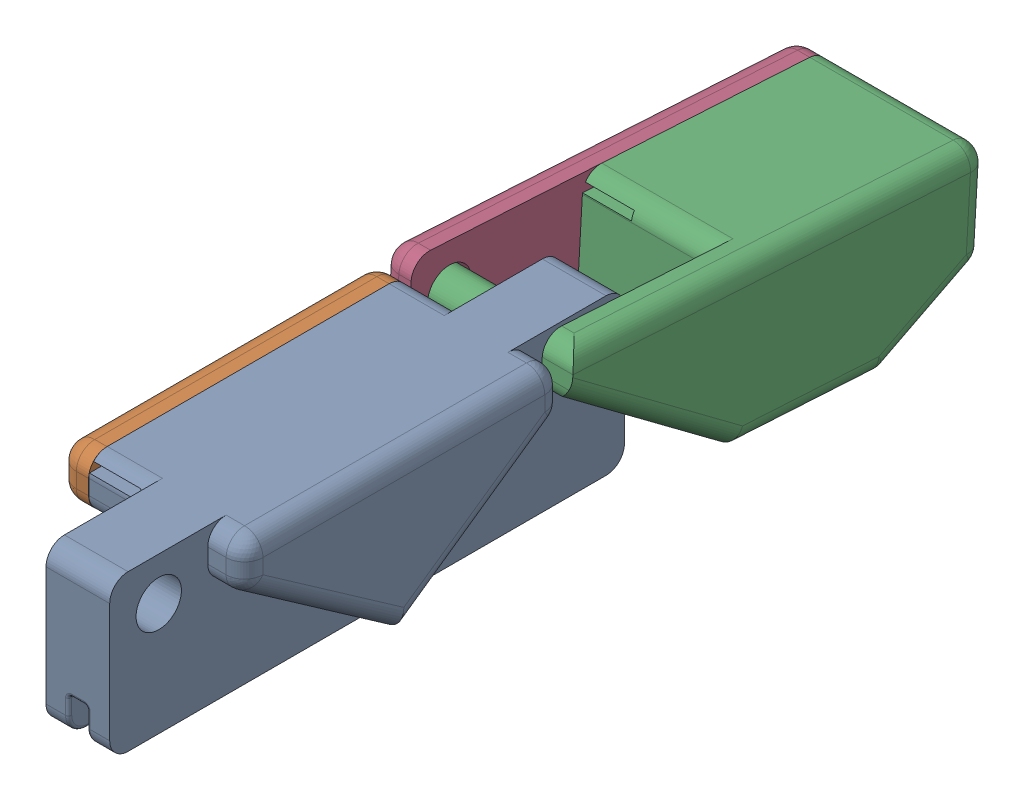
SolidWorks assembly thumb assembly, configuration Default. Lengths in mm.
Overall size (15.78 14.7 68.9).
4 component instances, 4 part files, 6 mates.
Components (placement in the parent):
- first_knuckle_michelle_R_1-1: first_knuckle_michelle_R_1 [Default] at (32.9702 5.7874 18.139) size (14.1 12.7 42)
- first_knuckle_michelle_L_1-1: first_knuckle_michelle_L_1 [Default] at (1.692 5.7874 21.0506) x (0 0 -1) z (1 0 0) size (26.02 12.36 2.5)
- last_knuckle_michelleR_1-1: last_knuckle_michelleR_1 [Default] at (42.5586 5.8292 -0.429) x (1 0 0) z (0 0.059368 0.998236) size (14.6 12.7 34)
- last_knuckle_michelle_L_1-1: last_knuckle_michelle_L_1 [Default] at (1.112 5.6934 -18.8504) x (0 -0.059368 -0.998236) z (0 -0.998236 0.059368) size (34 2.5 12.7)
Mates (geometry in assembly coordinates):
- Concentric1: concentric aligned: circle of first_knuckle_michelle_R_1-1; circle of first_knuckle_michelle_L_1-1
- Coincident1: coincident aligned: line of first_knuckle_michelle_R_1-1 through (4.192 18.4874 4.0948) axis (0 0 1); line of first_knuckle_michelle_L_1-1 through (4.192 18.4874 4.0948) axis (0 0 1)
- Concentric2: concentric anti-aligned: circle of last_knuckle_michelleR_1-1; circle of last_knuckle_michelle_L_1-1
- Coincident2: coincident aligned: line of last_knuckle_michelleR_1-1 through (3.612 16.7447 -30.8114) axis (0 0.059368 0.998236); line of last_knuckle_michelle_L_1-1 through (3.612 16.7447 -30.8114) axis (0 0.059368 0.998236)
- Concentric4: concentric aligned: circle of first_knuckle_michelle_R_1-1; circle of last_knuckle_michelle_L_1-1
- Distance4: distance = 5.08 mm: line of first_knuckle_michelle_R_1-1 through (8.692 18.4874 -3.9052) axis (0 0 1); line of last_knuckle_michelle_L_1-1 through (3.612 16.7447 -30.8114) axis (0 0.059368 0.998236)
